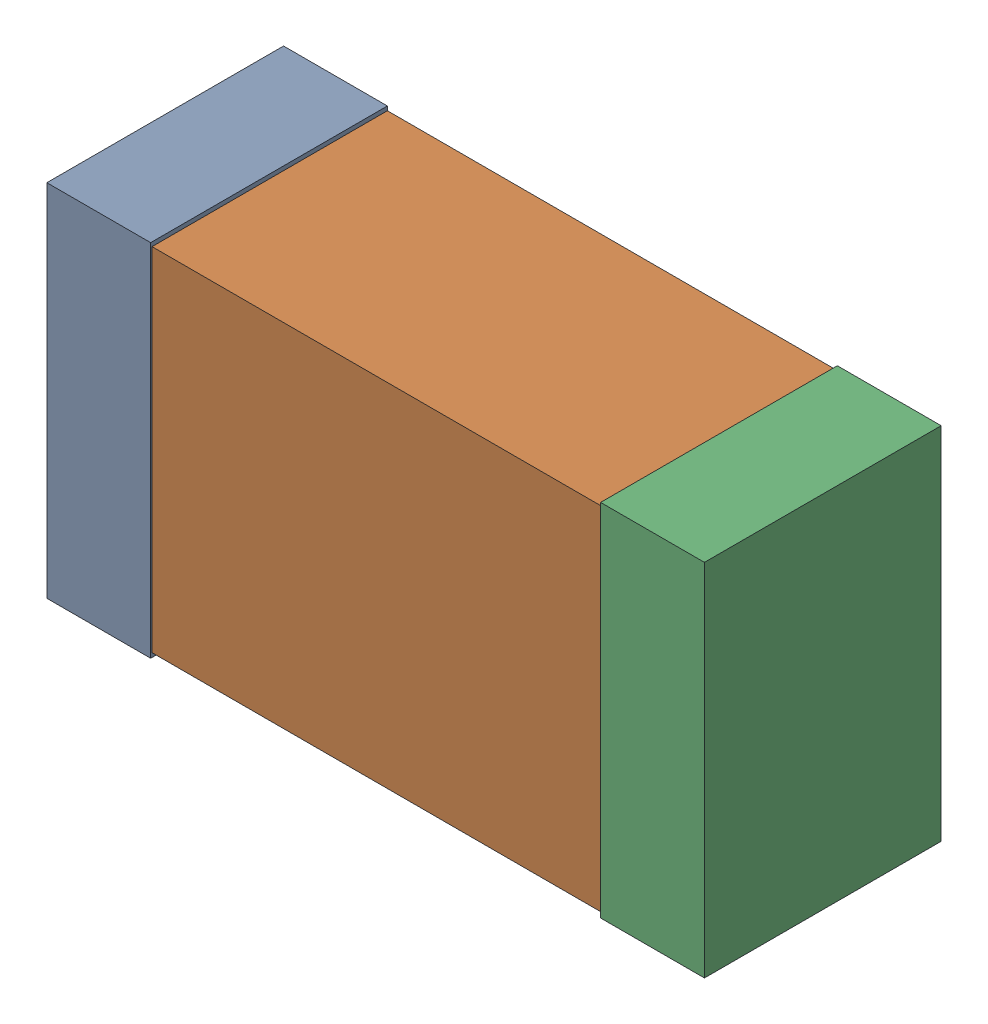
SolidWorks assembly C13_Motor_3Kanaloa_v2.0.0_Motor, configuration Default. Lengths in mm.
Overall size (2.38 1.3 0.85).
6 component instances, 2 part files, 0 mates.
Components (placement in the parent):
- 352877648-1: 352877648 [Default] at (59.901 87.63 0) size (0.38 1.3 0.85)
  - Extruded_14-1: Extruded_14 [Default] at origin size (0.38 1.3 0.85)
- 352877392-1: 352877392 [Default] at (60.901 87.63 0) size (2.2 1.27 0.85)
  - Extruded_15-1: Extruded_15 [Default] at origin size (2.2 1.27 0.85)
- 352877648-2: 352877648 [Default] at (61.901 87.63 0) size (0.38 1.3 0.85)
  - Extruded_14-1: Extruded_14 [Default] at origin size (0.38 1.3 0.85)
